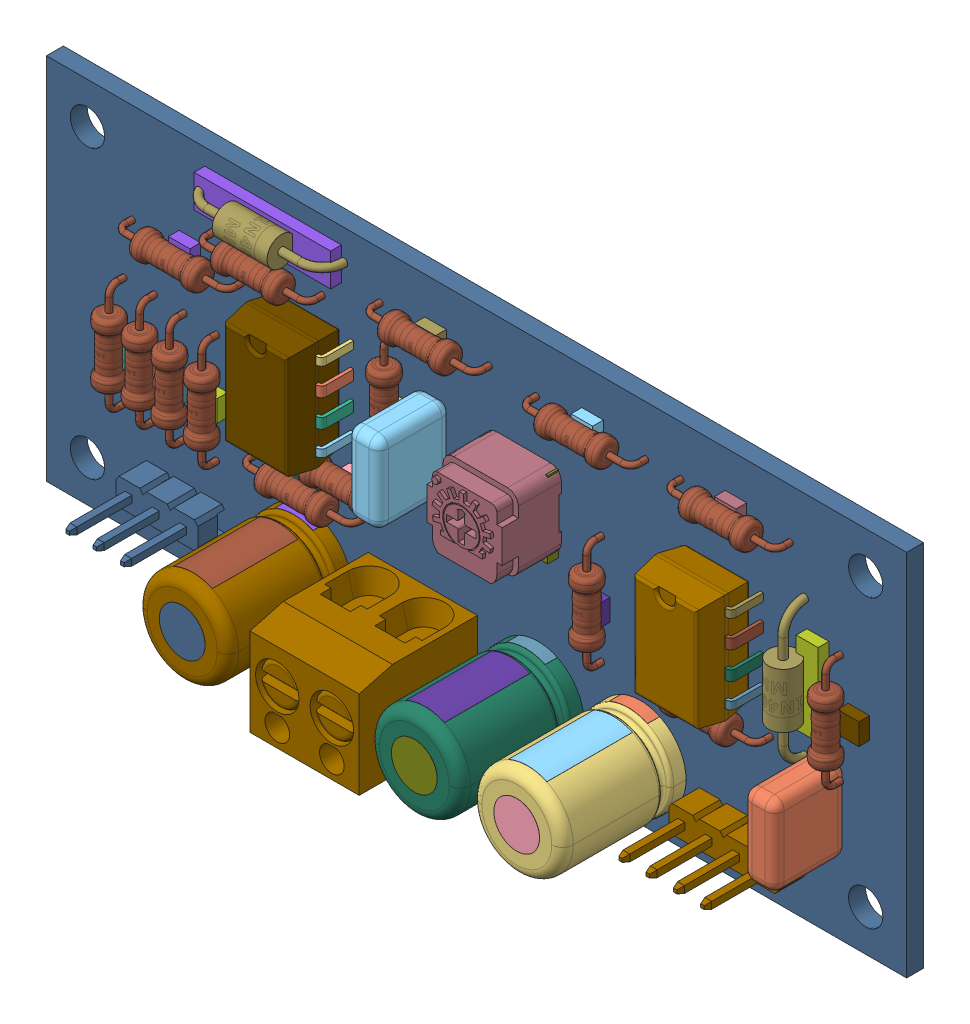
SolidWorks assembly servo control, configuration Standard. Lengths in mm.
Overall size (80.01 34.29 16.01).
83 component instances, 67 part files, 18 mates.
Components (placement in the parent):
- PPP5f11e933c2ba9.stp-1: PPP5f11e933c2ba9.stp [Standard] at origin size (80.01 34.29 16.01)
  - CAPPRD500W45D850H1150P001.stp-1: CAPPRD500W45D850H1150P001.stp [Standard] at (55.245 5.715 1.57) x (0 -1 0) z (0 0 1) size (0.45 0.45 2.54)
  - CAPPRD500W45D850H1150P004.stp-1: CAPPRD500W45D850H1150P004.stp [Standard] at (55.245 5.715 1.57) x (0 -1 0) z (0 0 1) size (0.41 3.61 1.15)
  - CAPPRD500W45D850H1150P005.stp-1: CAPPRD500W45D850H1150P005.stp [Standard] at (55.245 5.715 1.57) x (0 -1 0) z (0 0 1) size (8.5 8.5 11.5)
  - CAPPRD500W45D850H1150P002.stp-1: CAPPRD500W45D850H1150P002.stp [Standard] at (55.245 5.715 1.57) x (0 -1 0) z (0 0 1) size (4.25 4.25 0.01)
  - CAPPRD500W45D850H1150P003.stp-1: CAPPRD500W45D850H1150P003.stp [Standard] at (55.245 5.715 1.57) x (0 -1 0) z (0 0 1) size (0.41 3.61 7.96)
  - CAPPRD500W45D850H1150P.stp-1: CAPPRD500W45D850H1150P.stp [Standard] at (55.245 5.715 1.57) x (0 -1 0) z (0 0 1) size (0.45 0.45 2.54)
  - CAPPRD500W45D850H1150P006.stp-1: CAPPRD500W45D850H1150P006.stp [Standard] at (24.13 5.715 1.57) x (0 -1 0) z (0 0 1) size (0.45 0.45 2.54)
  - CAPPRD500W45D850H1150P007.stp-1: CAPPRD500W45D850H1150P007.stp [Standard] at (24.13 5.715 1.57) x (0 -1 0) z (0 0 1) size (0.41 3.61 1.15)
  - CAPPRD500W45D850H1150P008.stp-1: CAPPRD500W45D850H1150P008.stp [Standard] at (24.13 5.715 1.57) x (0 -1 0) z (0 0 1) size (8.5 8.5 11.5)
  - CAPPRD500W45D850H1150P009.stp-1: CAPPRD500W45D850H1150P009.stp [Standard] at (24.13 5.715 1.57) x (0 -1 0) z (0 0 1) size (4.25 4.25 0.01)
  - CAPPRD500W45D850H1150P010.stp-1: CAPPRD500W45D850H1150P010.stp [Standard] at (24.13 5.715 1.57) x (0 -1 0) z (0 0 1) size (0.41 3.61 7.96)
  - CAPPRD500W45D850H1150P011.stp-1: CAPPRD500W45D850H1150P011.stp [Standard] at (24.13 5.715 1.57) x (0 -1 0) z (0 0 1) size (0.45 0.45 2.54)
  - CAPPRD500W45D850H1150P012.stp-1: CAPPRD500W45D850H1150P012.stp [Standard] at (45.72 5.715 1.57) x (0 -1 0) z (0 0 1) size (0.45 0.45 2.54)
  - CAPPRD500W45D850H1150P013.stp-1: CAPPRD500W45D850H1150P013.stp [Standard] at (45.72 5.715 1.57) x (0 -1 0) z (0 0 1) size (0.41 3.61 1.15)
  - CAPPRD500W45D850H1150P014.stp-1: CAPPRD500W45D850H1150P014.stp [Standard] at (45.72 5.715 1.57) x (0 -1 0) z (0 0 1) size (8.5 8.5 11.5)
  - CAPPRD500W45D850H1150P015.stp-1: CAPPRD500W45D850H1150P015.stp [Standard] at (45.72 5.715 1.57) x (0 -1 0) z (0 0 1) size (4.25 4.25 0.01)
  - CAPPRD500W45D850H1150P016.stp-1: CAPPRD500W45D850H1150P016.stp [Standard] at (45.72 5.715 1.57) x (0 -1 0) z (0 0 1) size (0.41 3.61 7.96)
  - CAPPRD500W45D850H1150P017.stp-1: CAPPRD500W45D850H1150P017.stp [Standard] at (45.72 5.715 1.57) x (0 -1 0) z (0 0 1) size (0.45 0.45 2.54)
  - CAPRR500W50L750T300H680P001.stp-1: CAPRR500W50L750T300H680P001.stp [Standard] at (73.025 10.795 1.57) x (0 -1 0) z (0 0 1) size (0.5 0.5 6.8)
  - CAPRR500W50L750T300H680P002.stp-1: CAPRR500W50L750T300H680P002.stp [Standard] at (73.025 10.795 1.57) x (0 -1 0) z (0 0 1) size (7.5 3 6.8)
  - CAPRR500W50L750T300H680P.stp-1: CAPRR500W50L750T300H680P.stp [Standard] at (73.025 10.795 1.57) x (0 -1 0) z (0 0 1) size (0.5 0.5 6.8)
  - CAPRR500W50L750T300H680P003.stp-1: CAPRR500W50L750T300H680P003.stp [Standard] at (36.195 21.59 1.57) x (0 1 0) z (0 0 1) size (0.5 0.5 6.8)
  - CAPRR500W50L750T300H680P004.stp-1: CAPRR500W50L750T300H680P004.stp [Standard] at (36.195 21.59 1.57) x (0 1 0) z (0 0 1) size (7.5 3 6.8)
  - CAPRR500W50L750T300H680P005.stp-1: CAPRR500W50L750T300H680P005.stp [Standard] at (36.195 21.59 1.57) x (0 1 0) z (0 0 1) size (0.5 0.5 6.8)
  - Component_1.stp-1: Component_1.stp [Standard] at (71.755 19.685 1.57) x (0 1 0) z (0 0 1) size (7.62 2.03 1)
  - Component_2.stp-1: Component_2.stp [Standard] at (21.082 31.242 1.57) x (-1 0 0) z (0 0 1) size (12.7 3.05 1)
  - DIP762W45P254L1015H533Q8P008.stp-1: DIP762W45P254L1015H533Q8P008.stp [Standard] at (62.865 20.32 1.57) x (0 -1 0) z (0 0 1) size (10.15 6.49 5.1)
  - DIP762W45P254L1015H533Q8P001.stp-1: DIP762W45P254L1015H533Q8P001.stp [Standard] at (62.865 20.32 1.57) x (0 -1 0) z (0 0 1) size (0.95 0.57 3.1)
  - DIP762W45P254L1015H533Q8P006.stp-1: DIP762W45P254L1015H533Q8P006.stp [Standard] at (62.865 20.32 1.57) x (0 -1 0) z (0 0 1) size (0.95 0.57 3.1)
  - DIP762W45P254L1015H533Q8P007.stp-1: DIP762W45P254L1015H533Q8P007.stp [Standard] at (62.865 20.32 1.57) x (0 -1 0) z (0 0 1) size (0.7 0.57 3.1)
  - DIP762W45P254L1015H533Q8P003.stp-1: DIP762W45P254L1015H533Q8P003.stp [Standard] at (62.865 20.32 1.57) x (0 -1 0) z (0 0 1) size (0.7 0.57 3.1)
  - DIP762W45P254L1015H533Q8P004.stp-1: DIP762W45P254L1015H533Q8P004.stp [Standard] at (62.865 20.32 1.57) x (0 -1 0) z (0 0 1) size (0.7 0.57 3.1)
  - DIP762W45P254L1015H533Q8P005.stp-1: DIP762W45P254L1015H533Q8P005.stp [Standard] at (62.865 20.32 1.57) x (0 -1 0) z (0 0 1) size (0.95 0.57 3.1)
  - DIP762W45P254L1015H533Q8P002.stp-1: DIP762W45P254L1015H533Q8P002.stp [Standard] at (62.865 20.32 1.57) x (0 -1 0) z (0 0 1) size (0.95 0.57 3.1)
  - DIP762W45P254L1015H533Q8P.stp-1: DIP762W45P254L1015H533Q8P.stp [Standard] at (62.865 20.32 1.57) x (0 -1 0) z (0 0 1) size (0.7 0.57 3.1)
  - DIP762W45P254L1015H533Q8P009.stp-1: DIP762W45P254L1015H533Q8P009.stp [Standard] at (24.765 21.59 1.57) x (0 -1 0) z (0 0 1) size (10.15 6.49 5.1)
  - DIP762W45P254L1015H533Q8P010.stp-1: DIP762W45P254L1015H533Q8P010.stp [Standard] at (24.765 21.59 1.57) x (0 -1 0) z (0 0 1) size (0.95 0.57 3.1)
  - DIP762W45P254L1015H533Q8P011.stp-1: DIP762W45P254L1015H533Q8P011.stp [Standard] at (24.765 21.59 1.57) x (0 -1 0) z (0 0 1) size (0.95 0.57 3.1)
  - DIP762W45P254L1015H533Q8P012.stp-1: DIP762W45P254L1015H533Q8P012.stp [Standard] at (24.765 21.59 1.57) x (0 -1 0) z (0 0 1) size (0.7 0.57 3.1)
  - DIP762W45P254L1015H533Q8P013.stp-1: DIP762W45P254L1015H533Q8P013.stp [Standard] at (24.765 21.59 1.57) x (0 -1 0) z (0 0 1) size (0.7 0.57 3.1)
  - DIP762W45P254L1015H533Q8P014.stp-1: DIP762W45P254L1015H533Q8P014.stp [Standard] at (24.765 21.59 1.57) x (0 -1 0) z (0 0 1) size (0.7 0.57 3.1)
  - DIP762W45P254L1015H533Q8P015.stp-1: DIP762W45P254L1015H533Q8P015.stp [Standard] at (24.765 21.59 1.57) x (0 -1 0) z (0 0 1) size (0.95 0.57 3.1)
  - DIP762W45P254L1015H533Q8P016.stp-1: DIP762W45P254L1015H533Q8P016.stp [Standard] at (24.765 21.59 1.57) x (0 -1 0) z (0 0 1) size (0.95 0.57 3.1)
  - DIP762W45P254L1015H533Q8P017.stp-1: DIP762W45P254L1015H533Q8P017.stp [Standard] at (24.765 21.59 1.57) x (0 -1 0) z (0 0 1) size (0.7 0.57 3.1)
  - 1.stp-1: 1.stp [Standard] at (65.405 4.445 1.57) size (10.16 2.5 11.2)
  - 1001.stp-1: 1001.stp [Standard] at (12.7 5.08 1.57) size (7.62 2.5 11.2)
  - Component_3.stp-1: Component_3.stp [Standard] at (62.23 13.335 1.57) size (2 2 1)
  - Component_004.stp-1: Component_004.stp [Standard] at (36.195 29.845 1.57) x (-1 0 0) z (0 0 1) size (2 2 1)
  - Component_005.stp-1: Component_005.stp [Standard] at (64.135 29.845 1.57) x (-1 0 0) z (0 0 1) size (2 2 1)
  - Component_006.stp-1: Component_006.stp [Standard] at (12.7 14.605 1.57) x (0 1 0) z (0 0 1) size (2 2 1)
  - Component_007.stp-1: Component_007.stp [Standard] at (24.765 12.065 1.57) size (2 2 1)
  - Component_4.stp-1: Component_4.stp [Standard] at (44.45 19.05 1.57) x (-1 0 0) z (0 0 1) size (6.35 7.11 1)
  - Component_008.stp-1: Component_008.stp [Standard] at (51.435 15.875 1.57) x (0 -1 0) z (0 0 1) size (2 2 1)
  - Component_009.stp-1: Component_009.stp [Standard] at (75.565 18.415 1.57) x (0 1 0) z (0 0 1) size (2 2 1)
  - Component_010.stp-1: Component_010.stp [Standard] at (20.574 27.94 1.57) x (-1 0 0) z (0 0 1) size (2 2 1)
  - Component_011.stp-1: Component_011.stp [Standard] at (10.16 14.605 1.57) x (0 -1 0) z (0 0 1) size (2 2 1)
  - Component_012.stp-1: Component_012.stp [Standard] at (33.02 22.225 1.57) x (0 1 0) z (0 0 1) size (2 2 1)
  - Component_013.stp-1: Component_013.stp [Standard] at (29.21 14.605 1.57) size (2 2 1)
  - Component_014.stp-1: Component_014.stp [Standard] at (50.8 29.845 1.57) x (-1 0 0) z (0 0 1) size (2 2 1)
  - Component_015.stp-1: Component_015.stp [Standard] at (7.62 14.605 1.57) x (0 -1 0) z (0 0 1) size (2 2 1)
  - Component_016.stp-1: Component_016.stp [Standard] at (15.875 14.605 1.57) x (0 1 0) z (0 0 1) size (2 2 1)
  - Component_017.stp-1: Component_017.stp [Standard] at (13.335 25.4 1.57) x (-1 0 0) z (0 0 1) size (2 2 1)
  - HI_237-132.stp-1: HI_237-132.stp [Standard] at (34.925 4.445 1.57) x (-1 0 0) z (0 0 1) size (10.16 9 15.5)
  - Component_Component.stp-1: Component_Component.stp [Standard] at origin size (80.01 34.29 1.57)
- resitor v1-2: resitor v1 [Default] at (64.1184 29.7049 2.97) x (1 0 0) z (0 -1 0) size (10.69 2.62 2.44)
- resitor v1-3: resitor v1 [Default] at (50.6761 29.6713 2.97) x (1 0 0) z (0 -1 0) size (10.69 2.62 2.44)
- resitor v1-4: resitor v1 [Default] at (36.1332 29.9414 2.97) x (1 0.00005 0) z (0.00005 -1 0) size (10.69 2.62 2.44)
- resitor v1-6: resitor v1 [Default] at (28.7447 14.8598 2.97) x (1 0 0) z (0 -1 0) size (10.69 2.62 2.44)
- resitor v1-7: resitor v1 [Default] at (24.6467 11.9977 2.97) x (1 0 0) z (0 -1 0) size (10.69 2.62 2.44)
- resitor v1-8: resitor v1 [Default] at (20.5893 27.8448 2.97) x (1 0 0) z (0 -1 0) size (10.69 2.62 2.44)
- resitor v1-9: resitor v1 [Default] at (13.0811 25.0892 2.97) x (1 0 0) z (0 -1 0) size (10.69 2.62 2.44)
- resitor v1-12: resitor v1 [Default] at (62.2779 13.1316 2.97) x (1 0 0) z (0 -1 0) size (10.69 2.62 2.44)
- resitor v1-13: resitor v1 [Default] at (15.8411 14.6743 2.97) x (0 1 0) z (1 0 0) size (10.69 2.62 2.44)
- resitor v1-14: resitor v1 [Default] at (12.8282 14.8942 2.97) x (0 1 0) z (1 0 0) size (10.69 2.62 2.44)
- resitor v1-15: resitor v1 [Default] at (10.0587 15.0173 2.97) x (0 1 0) z (1 0 0) size (10.69 2.62 2.44)
- resitor v1-16: resitor v1 [Default] at (7.2261 14.9747 2.97) x (0 1 0) z (1 0 0) size (10.69 2.62 2.44)
- resitor v1-17: resitor v1 [Default] at (76.0113 20.0451 5.1) x (0 1 0) z (1 0 0) size (10.69 2.62 2.44)
- resitor v1-18: resitor v1 [Default] at (32.7975 23.5522 2.97) x (0 1 0) z (1 0 0) size (10.69 2.62 2.44)
- resitor v1-19: resitor v1 [Default] at (51.6569 16.3787 2.97) x (0 1 0) z (1 0 0) size (10.69 2.62 2.44)
- Rectifier Diode 1N4007-1: Rectifier Diode 1N4007 [Default] at (70.5326 19.5292 3.5784) x (0 1 0) z (1 0 0) size (13.4 3.36 2.7)
- Rectifier Diode 1N4007-3: Rectifier Diode 1N4007 [Default] at (21.3238 31.4886 3.5784) x (-1 0 0) z (0 1 0) size (13.4 3.36 2.7)
- TrimmerPot-1: TrimmerPot [Default] at (44.3936 21.442 1.57) x (1 0 0) z (0 -1 0) size (7 5.8 7)
Mates (geometry in assembly coordinates):
- Deckungsgleich1: coincident anti-aligned: plane of PPP5f11e933c2ba9.stp-1/Component_Component.stp-1 through (0 0 1.57) normal (0 0 1); plane of resitor v1-3 through (50.6761 29.6713 1.57) normal (0 0 -1)
- Deckungsgleich2: coincident anti-aligned: plane of PPP5f11e933c2ba9.stp-1/Component_Component.stp-1 through (0 0 1.57) normal (0 0 1); plane of resitor v1-2 through (64.1184 29.7049 1.57) normal (0 0 -1)
- Deckungsgleich3: coincident aligned: plane of PPP5f11e933c2ba9.stp-1/Component_Component.stp-1 through (0 0 1.57) normal (0 0 1); circle of resitor v1-4
- Deckungsgleich5: coincident anti-aligned: plane of PPP5f11e933c2ba9.stp-1/Component_Component.stp-1 through (0 0 1.57) normal (0 0 1); plane of resitor v1-8 through (20.5893 27.8448 1.57) normal (0 0 -1)
- Deckungsgleich6: coincident anti-aligned: plane of PPP5f11e933c2ba9.stp-1/Component_Component.stp-1 through (0 0 1.57) normal (0 0 1); plane of resitor v1-9 through (13.0811 25.0892 1.57) normal (0 0 -1)
- Deckungsgleich7: coincident anti-aligned: plane of PPP5f11e933c2ba9.stp-1/Component_Component.stp-1 through (0 0 1.57) normal (0 0 1); plane of resitor v1-7 through (24.6467 11.9977 1.57) normal (0 0 -1)
- Deckungsgleich8: coincident anti-aligned: plane of PPP5f11e933c2ba9.stp-1/Component_Component.stp-1 through (0 0 1.57) normal (0 0 1); plane of resitor v1-7 through (24.6467 11.9977 1.57) normal (0 0 -1)
- Deckungsgleich9: coincident anti-aligned: plane of PPP5f11e933c2ba9.stp-1/Component_Component.stp-1 through (0 0 1.57) normal (0 0 1); plane of resitor v1-6 through (28.7447 14.8598 1.57) normal (0 0 -1)
- Deckungsgleich11: coincident anti-aligned: plane of PPP5f11e933c2ba9.stp-1/Component_Component.stp-1 through (0 0 1.57) normal (0 0 1); plane of resitor v1-12 through (62.2779 13.1316 1.57) normal (0 0 -1)
- Deckungsgleich12: coincident anti-aligned: plane of PPP5f11e933c2ba9.stp-1/Component_Component.stp-1 through (0 0 1.57) normal (0 0 1); plane of resitor v1-13 through (15.8411 14.6743 1.57) normal (0 0 -1)
- Deckungsgleich14: coincident anti-aligned: plane of PPP5f11e933c2ba9.stp-1/Component_Component.stp-1 through (0 0 1.57) normal (0 0 1); plane of resitor v1-19 through (51.6569 16.3787 1.57) normal (0 0 -1)
- Deckungsgleich15: coincident anti-aligned: plane of PPP5f11e933c2ba9.stp-1/Component_Component.stp-1 through (0 0 1.57) normal (0 0 1); plane of resitor v1-18 through (32.7975 23.5522 1.57) normal (0 0 -1)
- Deckungsgleich16: coincident anti-aligned: plane of PPP5f11e933c2ba9.stp-1/Component_Component.stp-1 through (0 0 1.57) normal (0 0 1); plane of resitor v1-16 through (7.2261 14.9747 1.57) normal (0 0 -1)
- Deckungsgleich17: coincident anti-aligned: plane of PPP5f11e933c2ba9.stp-1/Component_Component.stp-1 through (0 0 1.57) normal (0 0 1); plane of resitor v1-14 through (12.8282 14.8942 1.57) normal (0 0 -1)
- Deckungsgleich18: coincident anti-aligned: plane of PPP5f11e933c2ba9.stp-1/Component_Component.stp-1 through (0 0 1.57) normal (0 0 1); plane of resitor v1-15 through (10.0587 15.0173 1.57) normal (0 0 -1)
- Deckungsgleich19: coincident aligned: plane of PPP5f11e933c2ba9.stp-1/Component_Component.stp-1 through (0 0 1.57) normal (0 0 1); circle of Rectifier Diode 1N4007-3
- Deckungsgleich20: coincident anti-aligned: plane of PPP5f11e933c2ba9.stp-1/Component_Component.stp-1 through (0 0 1.57) normal (0 0 1); plane of Rectifier Diode 1N4007-1 through (70.5326 19.5292 1.57) normal (0 0 -1)
- Deckungsgleich21: coincident anti-aligned: plane of PPP5f11e933c2ba9.stp-1/Component_Component.stp-1 through (0 0 1.57) normal (0 0 1); plane of TrimmerPot-1 through (41.8936 23.942 1.57) normal (0 0 -1)
